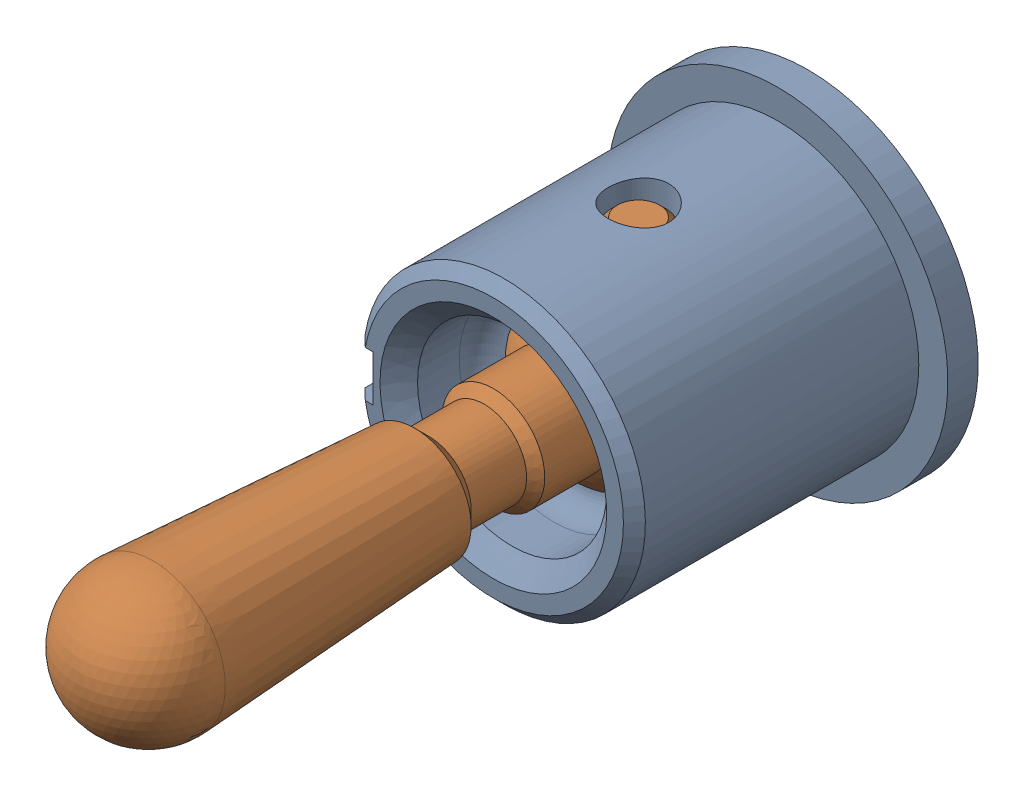
SolidWorks assembly MS Toggle Switch Sealed 3-Position Ref v1-1, configuration Default. Lengths in mm.
Overall size (14.29 14.29 30.73).
2 component instances, 2 part files, 0 mates.
Components (placement in the parent):
- Toggle Threads Sealed Ref -1: Toggle Threads Sealed Ref  [Default] at (-27.94 72.39 -5.2705) x (0 -1 0) z (0 0 1) size (14.29 14.29 13.21)
- Toggle Lever Sealed Ref-1: Toggle Lever Sealed Ref [Default] at (-27.94 72.39 -5.2705) x (0 -1 0) z (0 0 1) size (10.67 7.94 27.59)
